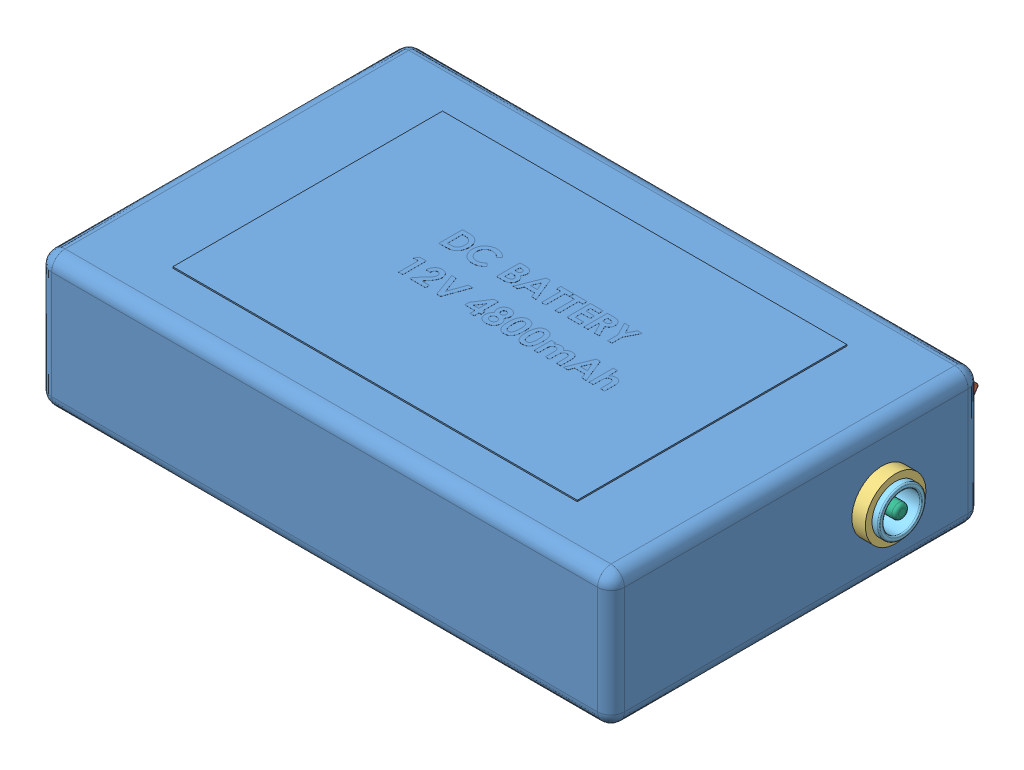
SolidWorks assembly Battery, configuration Default. Lengths in mm.
Overall size (88 20.21 59.22).
13 component instances, 8 part files, 6 mates.
Components (placement in the parent):
- battery_body-1: battery_body [Default] at (33.4598 40.6095 66.8775) size (85 20.21 55)
- Mini Rocker 4-Pin Switch-1: Mini Rocker 4-Pin Switch [Default] at (67.6398 50.3895 39.3775) x (-1 0 0) z (0 -1 0) size (10.64 14.37 14.84)
- dc_power_jack_assembly-1: dc_power_jack_assembly [Default] at (66.0649 52.0993 55.8301) x (1 0 0) z (0 0 -1) size (41 11.5 15)
  - main_body-1: main_body [Default] at (-16.1052 -4.2602 1.6818) size (34 11.5 15)
  - green_screw_section-1: green_screw_section [Default] at (-21.1052 -4.2602 6.6818) x (-1 0 0) z (0 0 -1) size (7 10 10)
  - jack_outer_metal-1: jack_outer_metal [Default] at (0.8948 1.4898 1.6818) x (0 0.735968 -0.677016) z (1 0 0) size (7 7 12)
  - jack_inner_rod-1: jack_inner_rod [Default] at (0.8948 1.4898 1.6818) x (0 0 -1) z (1 0 0) size (2.1 2.1 12)
  - wireholder_with_screw_assembly-1: wireholder_with_screw_assembly [Default] at (4.4628 17.1409 -69.445) x (0 0 -1) z (-1 0 0) size (4 9.26 5)
    - wireholder-1: wireholder [Default] at (-75.1268 12.4011 26.568) size (4 5.5 5)
    - pan cross head_ai-1: pan cross head_ai [CR-PHMS 0.06-80x0.125x0.125-N] at (-73.6268 21.1937 29.068) x (0 -1 0) z (0 0 1) size (4.26 2.95 2.95)
  - wireholder_with_screw_assembly-2: wireholder_with_screw_assembly [Default] at (4.4628 17.1409 -74.445) x (0 0 -1) z (-1 0 0) size (4 9.26 5)
    - wireholder-1: wireholder [Default] at (-75.1268 12.4011 26.568) size (4 5.5 5)
    - pan cross head_ai-1: pan cross head_ai [CR-PHMS 0.06-80x0.125x0.125-N] at (-73.6268 21.1937 29.068) x (0 -1 0) z (0 0 1) size (4.26 2.95 2.95)
Mates (geometry in assembly coordinates):
- Coincident1: coincident anti-aligned: plane of battery_body-1 through (-9.0402 60.6095 39.3775) normal (0 0 -1); plane of Mini Rocker 4-Pin Switch-1 through (67.6398 50.3895 39.3775) normal (0 0 1)
- Distance1: distance = 1 mm: line of Mini Rocker 4-Pin Switch-1 through (72.9598 56.7595 39.3775) axis (0 -1 0); line of battery_body-1 through (73.9598 58.6095 39.3775) axis (0 -1 0)
- Distance4: distance = 0.8 mm: line of Mini Rocker 4-Pin Switch-1 through (63.3698 57.8095 39.3775) axis (1 0 0); line of battery_body-1 through (-7.0402 58.6095 39.3775) axis (1 0 0)
- Concentric2: concentric: cylinder of battery_body-1 through (55.9598 50.6095 54.1483) axis (1 0 0) radius 4.5; cylinder of dc_power_jack_assembly-1/main_body-1 through (149.9442 50.6095 54.1483) axis (-1 0 0) radius 4.5
- Parallel2: parallel: plane of battery_body-1 through (33.4598 40.6095 66.8775) normal (0 -1 0); plane of dc_power_jack_assembly-1/main_body-1 through (121.9442 44.8595 54.1483) normal (0 -1 0)
- Distance6: distance = 2 mm aligned: plane of dc_power_jack_assembly-1/main_body-1 through (77.9598 50.6095 54.1483) normal (1 0 0); plane of battery_body-1 through (75.9598 60.6095 94.3775) normal (1 0 0)
